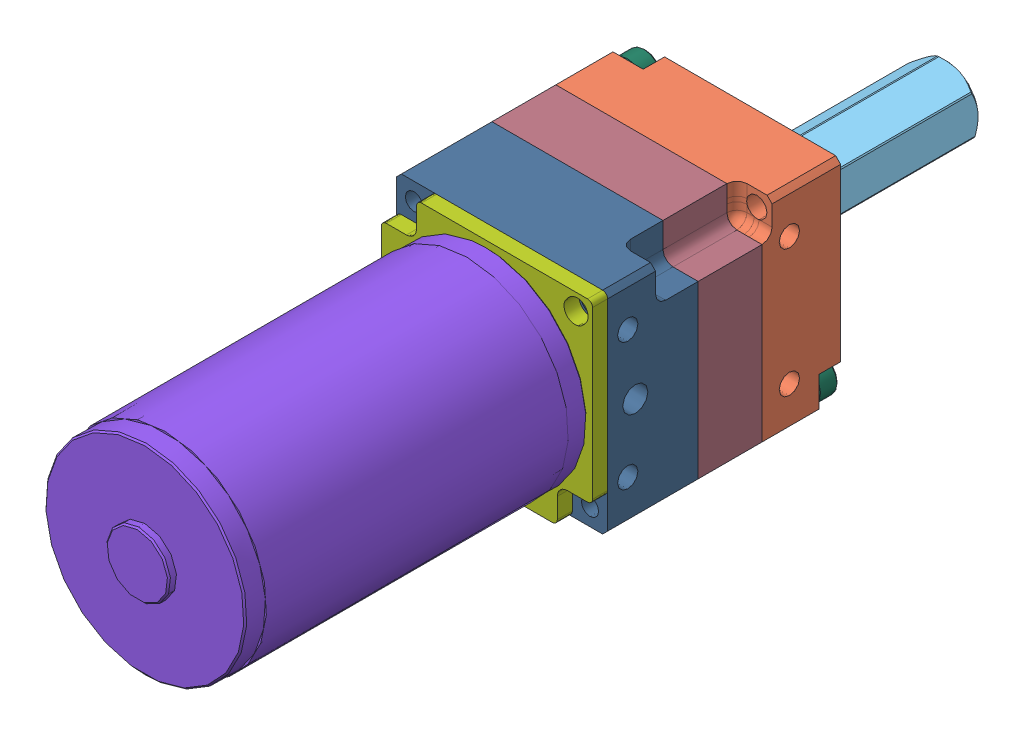
SolidWorks assembly VersaPlanetary_v1_Single_Stage_10_1_with_BAG1, configuration Default. Lengths in mm.
Overall size (62.06 62.06 160.81).
22 component instances, 15 part files, 0 mates.
Components (placement in the parent):
- 217-2742-001 Rev4_1-1: 217-2742-001 Rev4_1 [Default] at (0 0 -19.9002) x (0 0 1) z (-1 0 0) size (7 28 28)
- 217-2742-001 Rev4_1-2: 217-2742-001 Rev4_1 [Default] at (0 0 -28.305) x (0 0 1) z (-0.819238 -0.573454 0) size (7 28 28)
- 217-2625-002 Rev1_1-1: 217-2625-002 Rev1_1 [Default] at (0 0 -6.2) x (-1 0 0) z (0 0 1) size (42 42 17.13)
- 217-2625-018 Rev1_98541A410_1-1: 217-2625-018 Rev1_98541A410_1 [Default] at (0 0 -12.4002) x (0 0 -1) z (0.980859 -0.194721 0) size (1 19.6 17.4)
- 217-2625-017 Rev1_9714K61_1-1: 217-2625-017 Rev1_9714K61_1 [Default] at (0 0 -20.9002) x (-0.695225 0.718792 0) z (-0.718792 -0.695225 0) size (28.51 4.98 30.18)
- Ouput Shafts^VersaPlanetary_500 Hex_1-1: Ouput Shafts^VersaPlanetary_500 Hex_1 [Default] at (0 0 -20.5526) x (-0.995515 -0.094608 0) z (0 0 -1) size (17 17 64.12)
  - 217-2625-003 Rev1_1-1: 217-2625-003 Rev1_1 [Default] at origin size (17 17 64.12)
- 217-3564-000 Rev1_BAG_1-1: 217-3564-000 Rev1_BAG_1 [Default] at (0 0 18) size (42 42 81.5)
  - 217-2625-011 Rev1_2-1: 217-2625-011 Rev1_2 [Default] at (0 0 -5.25) x (1 0 0) z (0 -1 0) size (8.01 7.5 7.94)
  - 217-2822-003 Rev4_1-1: 217-2822-003 Rev4_1 [Default] at (0 0 1.5) size (42 42 4.8)
  - 217-3351_2-1: 217-3351_2 [Default] at (0 0 3) x (0 1 0) z (0 0 -1) size (40.4 40.4 81.5)
- Input Housing^VersaPlanetary_1-1: Input Housing^VersaPlanetary_1 [Default] at (-18.5 13.6657 1) x (0 0 -1) z (-0.885621 0.464408 0) size (20 56.7 56.7)
  - PINL-M020-006-S_2-1: PINL-M020-006-S_2 [Default] at origin size (6 2 2)
  - 217-2625-001 Rev1_1-1: 217-2625-001 Rev1_1 [Default] at (-9.5 3.511 -22.7304) x (0 -0.464408 -0.885621) z (-1 0 0) size (42 42 18)
  - 217-2625-009 Rev1_1-1: 217-2625-009 Rev1_1 [Default] at (-6.02 3.511 -22.7304) x (0 0.885621 -0.464408) z (1 0 0) size (18 18 13)
  - SSS1032-0125ZB_94105A824_1-1: SSS1032-0125ZB_94105A824_1 [Default] at (-11.495 6.7192 -16.6126) x (-0.636804 0.682837 -0.35807) z (0 0.464408 0.885621) size (4.83 4.84 3.3)
- 217-2816 Rev1_1-1: 217-2816 Rev1_1 [Default] at (0 0 -6.35) x (1 0 0) z (0 0 -1) size (42 42 14.5)
  - 217-2816-001 Rev1_1-1: 217-2816-001 Rev1_1 [Default] at origin size (42 42 14.5)
- 217-2817 Rev1_1-1: 217-2817 Rev1_1 [Default] at (0 0 -10.8) x (-0.517538 0.85566 0) z (0 0 -1) size (21.94 21.95 12.7)
  - 217-2724-001 Rev1_Sun_Driver01_1-1: 217-2724-001 Rev1_Sun_Driver01_1 [Default] at (0 0 -6.375) x (0.984808 0.173648 0) z (0 0 1) size (18.94 18.95 12.7)
- SSA_SSA0832-1250ZC_1-1: SSA_SSA0832-1250ZC_1 [Default] at (-17.5 17.5 -24.061) x (0.699203 0.714923 0) z (-0.714923 0.699203 0) size (6.73 35.81 6.73)
- SSA_SSA0832-1250ZC_1-2: SSA_SSA0832-1250ZC_1 [Default] at (17.5 -17.5 -24.061) x (-0.999999 0.001665 0) z (-0.001665 -0.999999 0) size (6.73 35.81 6.73)
